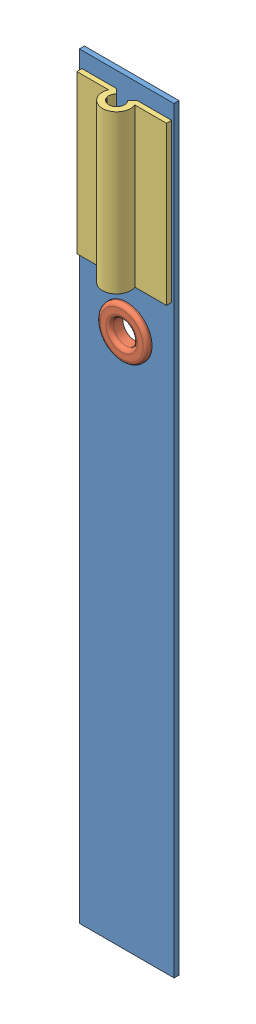
SolidWorks assembly grommet_assy, configuration Default. Lengths in mm.
Overall size (19.05 152.4 6.48).
3 component instances, 3 part files, 5 mates.
Components (placement in the parent):
- webbing_grommet_V1-1: webbing_grommet_V1 [Default] at (21.2356 27.4983 171.1427) size (19.05 152.4 1.02)
- grommet_V1-1: grommet_V1 [Default] at (21.2356 135.4483 170.5712) x (1 0 0) z (0 -1 0) size (10.16 2.6 10.16)
- yellow_cord_guide-1: yellow_cord_guide [Default] at (21.2356 176.7233 174.1907) x (1 0 0) z (0 -1 0) size (18.04 4.89 31.75)
Mates (geometry in assembly coordinates):
- Concentric1: concentric: cylinder of webbing_grommet_V1-1 through (21.2356 135.4483 171.1427) axis (0 0 1) radius 3.175; cylinder of grommet_V1-1 through (21.2356 135.4483 172.1587) axis (0 0 -1) radius 2.3813
- Coincident1: coincident: plane of webbing_grommet_V1-1 through (21.2356 27.4983 172.1587) normal (0 0 1); plane of grommet_V1-1 through (21.2356 135.4483 172.1587) normal (0 0 -1)
- Coincident2: coincident: plane of webbing_grommet_V1-1 through (21.2356 27.4983 172.1587) normal (0 0 1); plane of yellow_cord_guide-1 through (23.2676 159.1053 172.1587) normal (0 0 -1)
- Coincident3: coincident: plane of webbing_grommet_V1-1 through (21.2356 27.4983 171.1427) normal (1 0 0); plane of yellow_cord_guide-1 through (21.2356 176.7233 174.1907) normal (1 0 0)
- Distance1: distance = 3.175 mm: plane of yellow_cord_guide-1 through (21.2356 176.7233 174.1907) normal (0 1 0); plane of webbing_grommet_V1-1 through (11.7106 179.8983 172.1587) normal (0 1 0)
